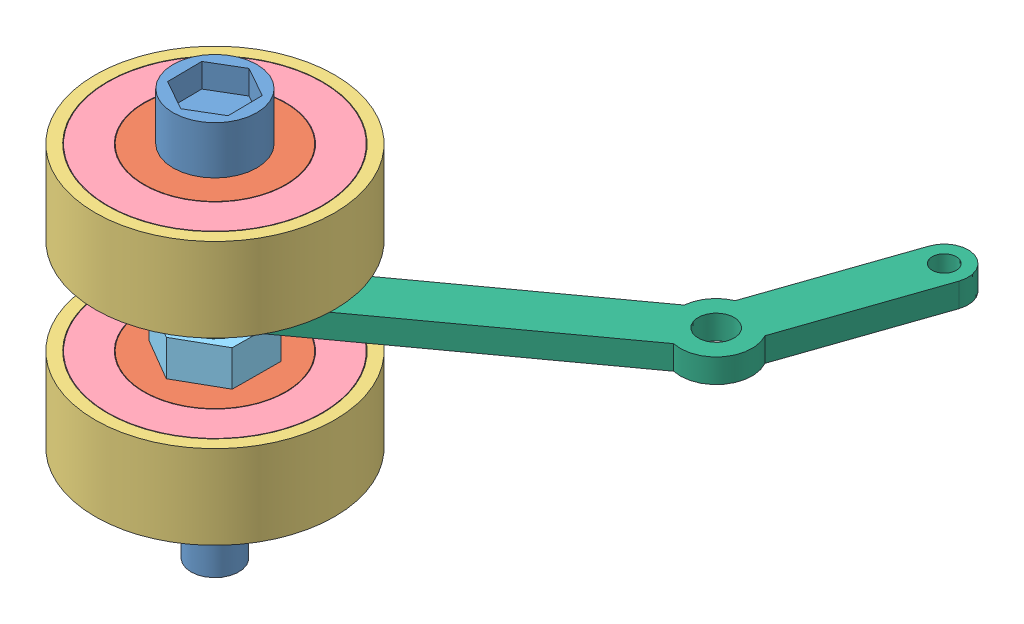
SolidWorks assembly 下导轮, configuration 默认. Lengths in mm.
Overall size (47.59 34 44.61).
13 component instances, 6 part files, 12 mates.
Components (placement in the parent):
- 下螺栓-1: 下螺栓 [默认] at (-13.5888 36.5642 40.1657) size (7 34 7)
- 轴承-1: 轴承 [默认] at (-8.5233 19.0642 40.969) x (1 0 0) z (0 1 0) size (20 20 7)
  - 轴承内圈-1: 轴承内圈 [默认] at (-5.0655 0.8032 6.5) size (11.8 11.8 7)
  - 轴承外圈-1: 轴承外圈 [默认] at (-5.0655 0.8032 6.5) size (20 20 7)
  - 轴承中圈-1: 轴承中圈 [默认] at (-5.0655 0.8032 6.5) size (17.9 17.9 7)
- 下部螺母-2: 下部螺母 [默认] at (-13.5888 25.5642 40.1657) x (1 0 0) z (0 -1 0) size (7.03 8.08 3.23)
- 下部连接-1: 下部连接 [默认] at (-13.5888 20.5642 40.1657) x (0.808943 0 -0.587887) z (0 1 0) size (47.29 13.6 2)
- 下部螺母-3: 下部螺母 [默认] at (-13.5888 20.5642 40.1657) x (1 0 0) z (0 -1 0) size (7.03 8.08 3.23)
- 轴承-2: 轴承 [默认] at (-8.5233 4.0642 40.969) x (1 0 0) z (0 1 0) size (20 20 7)
  - 轴承内圈-1: 轴承内圈 [默认] at (-5.0655 0.8032 6.5) size (11.8 11.8 7)
  - 轴承外圈-1: 轴承外圈 [默认] at (-5.0655 0.8032 6.5) size (20 20 7)
  - 轴承中圈-1: 轴承中圈 [默认] at (-5.0655 0.8032 6.5) size (17.9 17.9 7)
- 下部螺母-4: 下部螺母 [默认] at (-13.5888 10.5642 40.1657) x (1 0 0) z (0 -1 0) size (7.03 8.08 3.23)
Mates (geometry in assembly coordinates):
- 同心1: concentric: cylinder of 下螺栓-1 through (-13.5888 2.5642 40.1657) axis (0 1 0) radius 2; cylinder of ? through (-13.5888 32.5642 40.1657) axis (0 -1 0) radius 2
- 重合1: coincident: plane of 下螺栓-1 through (-13.5888 32.5642 40.1657) normal (0 -1 0); plane of ? through (-13.5888 32.5642 40.1657) normal (0 1 0)
- 同心2: concentric: cylinder of assembly; cylinder of assembly; cylinder of 下螺栓-1 through (-13.5888 2.5642 40.1657) axis (0 1 0) radius 2; cylinder of 下部螺母-2 through (-13.5888 25.5642 40.1657) axis (0 -1 0) radius 2
- 重合2: coincident: plane of ? through (-13.5888 25.5642 40.1657) normal (0 -1 0); plane of 下部螺母-2 through (-13.5888 25.5642 40.1657) normal (0 1 0)
- 同心4: concentric: cylinder of assembly; cylinder of assembly; cylinder of 下螺栓-1 through (-13.5888 2.5642 40.1657) axis (0 1 0) radius 2; cylinder of 下部螺母-3 through (-13.5888 20.5642 40.1657) axis (0 -1 0) radius 2
- 同心5: concentric: cylinder of 下螺栓-1 through (-13.5888 2.5642 40.1657) axis (0 1 0) radius 2; cylinder of ? through (-13.5888 17.5642 40.1657) axis (0 -1 0) radius 2
- 重合5: coincident: plane of 下部螺母-3 through (-13.5888 17.5642 40.1657) normal (0 -1 0); plane of ? through (-13.5888 17.5642 40.1657) normal (0 1 0)
- 同心6: concentric: cylinder of assembly; cylinder of assembly; cylinder of 下螺栓-1 through (-13.5888 2.5642 40.1657) axis (0 1 0) radius 2; cylinder of 下部螺母-4 through (-13.5888 10.5642 40.1657) axis (0 -1 0) radius 2
- 重合6: coincident: plane of ? through (-13.5888 10.5642 40.1657) normal (0 -1 0); plane of 下部螺母-4 through (-13.5888 10.5642 40.1657) normal (0 1 0)
- 重合7: coincident: plane of assembly; plane of assembly; plane of 下部连接-1 through (10.6795 20.5642 22.5291) normal (0 -1 0); plane of 下部螺母-3 through (-13.5888 20.5642 40.1657) normal (0 1 0)
- 同心7: concentric: cylinder of assembly; cylinder of assembly; cylinder of 下螺栓-1 through (-13.5888 2.5642 40.1657) axis (0 1 0) radius 2; cylinder of 下部连接-1 through (-13.5888 20.5642 40.1657) axis (0 1 0) radius 2
- 重合8: coincident: plane of assembly; plane of assembly; plane of 下部螺母-2 through (-13.5888 22.5642 40.1657) normal (0 -1 0); plane of 下部连接-1 through (10.6795 22.5642 22.5291) normal (0 1 0)
